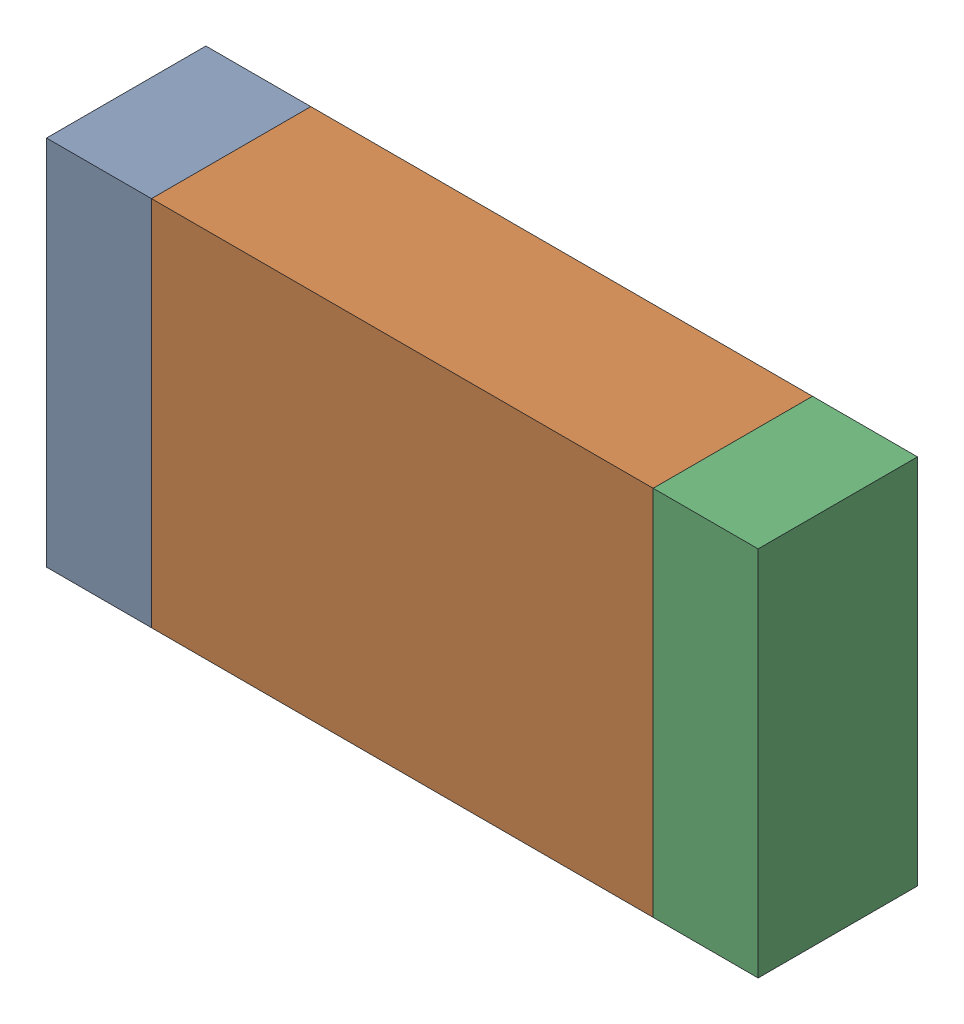
SolidWorks assembly R03-1, configuration Default. Lengths in mm.
Overall size (3.35 1.75 0.75).
6 component instances, 2 part files, 0 mates.
Components (placement in the parent):
- 959206760-1-1: 959206760-1 [Default] at (147.8506 77.6516 0) size (0.49 1.75 0.75)
  - Extruded-33-1: Extruded-33 [Default] at origin size (0.49 1.75 0.75)
- 959206896-1-1: 959206896-1 [Default] at (149.2781 77.6516 0) size (2.36 1.75 0.75)
  - Extruded-34-1: Extruded-34 [Default] at origin size (2.36 1.75 0.75)
- 959206760-1-2: 959206760-1 [Default] at (150.7056 77.6516 0) size (0.49 1.75 0.75)
  - Extruded-33-1: Extruded-33 [Default] at origin size (0.49 1.75 0.75)
